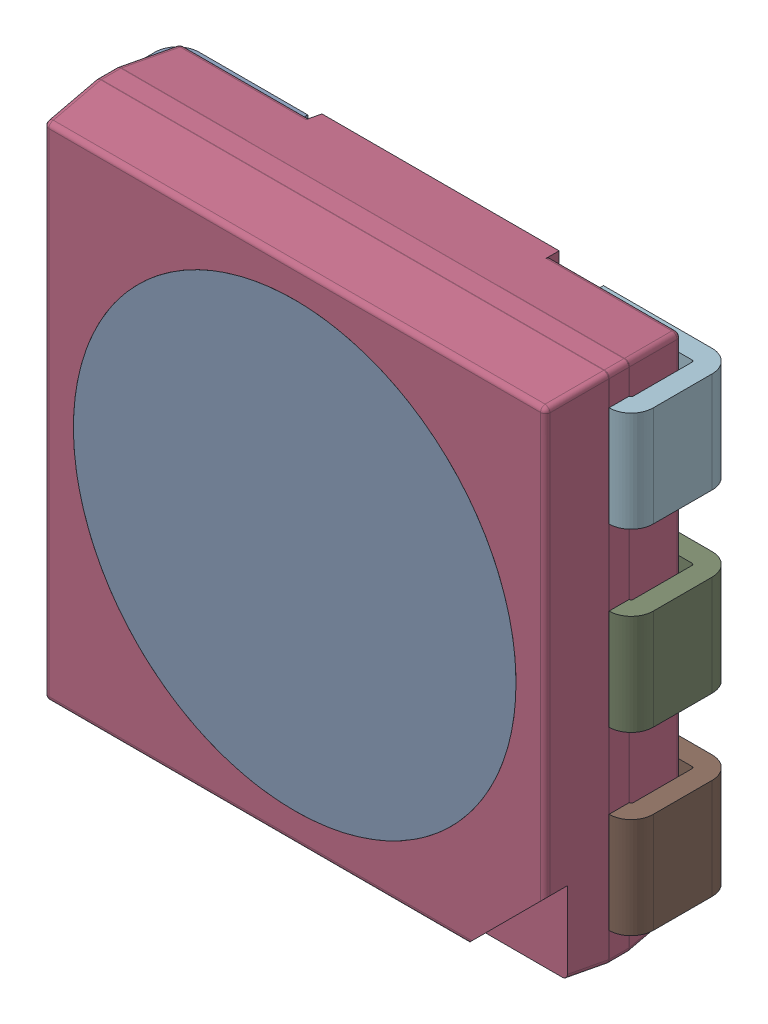
SolidWorks assembly User Library-5050 RGB led_7252440064, configuration Default. Lengths in mm.
Overall size (5.54 5.1 1.61).
8 component instances, 2 part files, 0 mates.
Components (placement in the parent):
- User Library-5050 RGB led_Body-1: User Library-5050 RGB led_Body [Default] at (-2.55 -2.55 0.25) size (5.1 5.1 1.46)
  - 1-1: 1 [Default] at origin size (5.1 5.1 1.46)
- User Library-5050 RGB led_Lead-1: User Library-5050 RGB led_Lead [Default] at (1.47 0 0) size (1.3 1 1.03)
- User Library-5050 RGB led_Lead-2: User Library-5050 RGB led_Lead [Default] at (-1.47 0 0) x (-1 0 0) z (0 0 1) size (1.3 1 1.03)
- User Library-5050 RGB led_Lead-3: User Library-5050 RGB led_Lead [Default] at (1.47 -1.75 0) size (1.3 1 1.03)
- User Library-5050 RGB led_Lead-4: User Library-5050 RGB led_Lead [Default] at (1.47 1.75 0) size (1.3 1 1.03)
- User Library-5050 RGB led_Lead-5: User Library-5050 RGB led_Lead [Default] at (-1.47 1.75 0) x (-1 0 0) z (0 0 1) size (1.3 1 1.03)
- User Library-5050 RGB led_Lead-6: User Library-5050 RGB led_Lead [Default] at (-1.47 -1.75 0) x (-1 0 0) z (0 0 1) size (1.3 1 1.03)
